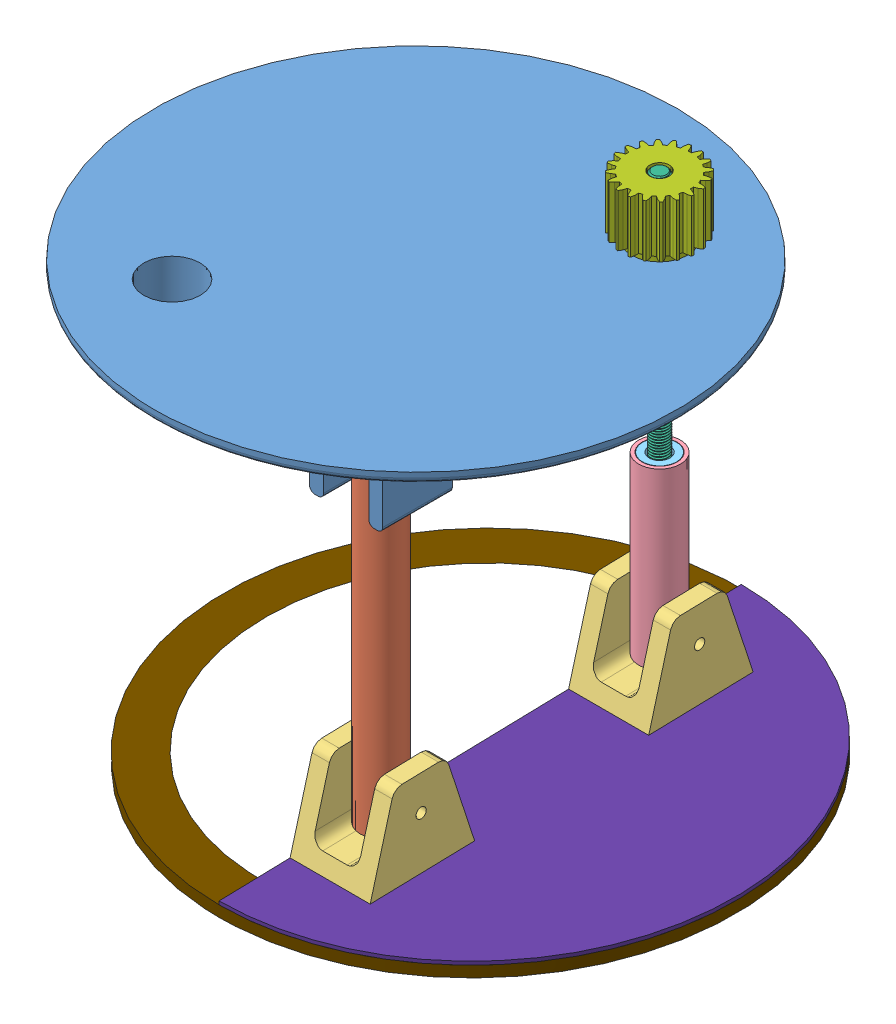
SolidWorks assembly Mıknatıslı lineer yan devirme, configuration Varsayılan. Lengths in mm.
Overall size (168.5 136.91 150.15).
20 component instances, 18 part files, 25 mates.
Components (placement in the parent):
- üst tabla-1: üst tabla [Varsayılan] at (-14.6467 18.8833 150) size (150 23 150)
- 16x100 karbon boru-2: 16x100 karbon boru [Varsayılan] at (15.3533 16.8833 190.0024) x (0 0.000298 -1) z (-1 0 0) size (12 100 12)
- tutturma parçası-5: tutturma parçası [Varsayılan] at (26.8533 -90.112 189.6) x (0 -0.025 0.999687) z (-1 0 0) size (30 25 23)
- tutturma parçası-6: tutturma parçası [Varsayılan] at (26.8533 -88.112 109.625) x (0 -0.025 0.999687) z (-1 0 0) size (30 25 23)
- 12x50-1: 12x50 [Varsayılan] at (15.3533 -81.1167 110) x (0 0 1) z (-1 0 0) size (12 50 12)
- somun yuvası-1: somun yuvası [Varsayılan] at (15.3533 -41.1167 110) x (0.299939 0 -0.953959) z (0.953959 0 0.299939) size (9.8 10 9.8)
- Yivli mil-1: Yivli mil [Varsayılan] at (15.3533 -41.1167 110) x (-0.194357 0 0.980931) z (-0.980931 0 -0.194357) size (5.15 80.6 5.79)
- Z20 pinion Module 1-1: Z20 pinion Module 1 [Default] at (15.3533 28.8833 110) x (0 -1 0) z (0.94071 0 -0.339213) size (26 21.82 21.82)
- inafag_625-2z_6leky27aadc6c6egwocnas8n-1: inafag_625-2z_6leky27aadc6c6egwocnas8n [Default] at (15.3533 7.8833 110) x (0 1 0) z (0.509017 0 0.860756) size (5.01 16 16)
  - inafag_625-2z_6leky27aadc6c6egwocnas8n_01-1: inafag_625-2z_6leky27aadc6c6egwocnas8n_01 [Default] at origin size (5 16 16)
  - inafag_625-2z_6leky27aadc6c6egwocnas8n_02-1: inafag_625-2z_6leky27aadc6c6egwocnas8n_02 [Default] at origin size (5.01 8.5 8.5)
  - inafag_625-2z_6leky27aadc6c6egwocnas8n_03-1: inafag_625-2z_6leky27aadc6c6egwocnas8n_03 [Default] at origin size (3.8 11.99 11.99)
  - inafag_625-2z_6leky27aadc6c6egwocnas8n_04-1: inafag_625-2z_6leky27aadc6c6egwocnas8n_04 [Default] at origin size (4.05 4.13 4.2)
  - inafag_625-2z_6leky27aadc6c6egwocnas8n_05-1: inafag_625-2z_6leky27aadc6c6egwocnas8n_05 [Default] at origin size (3.85 4.1 3.78)
  - inafag_625-2z_6leky27aadc6c6egwocnas8n_06-1: inafag_625-2z_6leky27aadc6c6egwocnas8n_06 [Default] at origin size (3.6 4.12 3.67)
  - inafag_625-2z_6leky27aadc6c6egwocnas8n_07-1: inafag_625-2z_6leky27aadc6c6egwocnas8n_07 [Default] at origin size (4.06 4.14 4.12)
  - inafag_625-2z_6leky27aadc6c6egwocnas8n_08-1: inafag_625-2z_6leky27aadc6c6egwocnas8n_08 [Default] at origin size (0.3 13.2 13.2)
  - inafag_625-2z_6leky27aadc6c6egwocnas8n_09-1: inafag_625-2z_6leky27aadc6c6egwocnas8n_09 [Default] at origin size (0.3 13.2 13.2)
- metal tabla-1: metal tabla [Varsayılan] at (3.8533 -90.1218 149.9894) x (0 0.025 -0.999687) z (1 0 0) size (150 1 75)
- mıknatıs savar-1: mıknatıs savar [Varsayılan] at (3.8533 -90.1218 149.9894) x (1 0 0) z (0 -0.025 0.999687) size (150 7.83 150)
Mates (geometry in assembly coordinates):
- Concentric26: concentric anti-aligned: cylinder of üst tabla-1 through (0.6107 8.8833 190) axis (1 0 0) radius 1.5; cylinder of 16x100 karbon boru-2 through (21.3533 8.8833 190) axis (-1 0 0) radius 1.5
- Concentric29: concentric anti-aligned: cylinder of 16x100 karbon boru-2 through (21.3533 -75.1167 189.975) axis (-1 0 0) radius 1.5; cylinder of tutturma parçası-5 through (3.8533 -75.1167 189.975) axis (1 0 0) radius 1.5
- Distance7: distance = 0.5 mm anti-aligned: plane of tutturma parçası-5 through (8.8533 -84.7386 174.7297) normal (1 0 0); cylinder of 16x100 karbon boru-2 through (15.3533 -83.1167 189.9726) axis (0 1 0.000298) radius 6
- Concentric30: concentric anti-aligned: cylinder of tutturma parçası-6 through (3.8533 -73.1167 110) axis (1 0 0) radius 1.5; cylinder of 12x50-1 through (21.3533 -73.1167 110) axis (-1 0 0) radius 1.5
- Distance8: distance = 0.5 mm anti-aligned: cylinder of 12x50-1 through (15.3533 -31.1167 110) axis (0 -1 0) radius 6; plane of tutturma parçası-6 through (21.8533 -82.7386 94.7547) normal (-1 0 0)
- Concentric31: concentric aligned: cylinder of 12x50-1 through (15.3533 -31.1167 110) axis (0 -1 0) radius 5; cylinder of somun yuvası-1 through (15.3533 -31.1167 110) axis (0 -1 0) radius 4.9
- Coincident1: coincident aligned: plane of 12x50-1 through (15.3533 -31.1167 110) normal (0 1 0); plane of somun yuvası-1 through (15.3533 -31.1167 110) normal (0 1 0)
- Concentric32: concentric anti-aligned: cylinder of üst tabla-1 through (15.3533 7.8833 110) axis (0 1 0) radius 8.1; cylinder of Yivli mil-1 through (15.3533 38.8833 110) axis (0 -1 0) radius 2.5
- Concentric33: concentric anti-aligned: cylinder of somun yuvası-1 through (15.3533 -41.1167 110) axis (0 1 0) radius 3; cylinder of Yivli mil-1 through (15.3533 38.8833 110) axis (0 -1 0) radius 2.5
- Concentric34: concentric aligned: cylinder of Yivli mil-1 through (15.3533 38.8833 110) axis (0 -1 0) radius 2.5; cylinder of Z20 pinion Module 1-1 through (15.3533 12.8833 110) axis (0 -1 0) radius 2.8
- Coincident2: coincident aligned: plane of Yivli mil-1 through (15.3533 38.8833 110) normal (0 1 0); plane of Z20 pinion Module 1-1 through (15.3533 38.8833 110) normal (0 1 0)
- Concentric35: concentric anti-aligned: cylinder of üst tabla-1 through (15.3533 7.8833 110) axis (0 1 0) radius 8.1; cylinder of inafag_625-2z_6leky27aadc6c6egwocnas8n-1/inafag_625-2z_6leky27aadc6c6egwocnas8n_01-1 through (15.3533 10.3833 110) axis (0 -1 0) radius 8
- Parallel1: parallel aligned: plane of tutturma parçası-5 through (3.8533 -89.737 174.6047) normal (0 -0.999687 -0.025); plane of tutturma parçası-6 through (3.8533 -87.737 94.6297) normal (0 -0.999687 -0.025)
- Coincident8: coincident anti-aligned: plane of Z20 pinion Module 1-1 through (15.3533 12.8833 110) normal (0 -1 0); plane of inafag_625-2z_6leky27aadc6c6egwocnas8n-1/inafag_625-2z_6leky27aadc6c6egwocnas8n_02-1 through (17.1476 12.8833 113.0342) normal (0 1 0)
- Coincident9: coincident anti-aligned: plane of üst tabla-1 through (15.3533 7.8833 110) normal (0 1 0); plane of inafag_625-2z_6leky27aadc6c6egwocnas8n-1/inafag_625-2z_6leky27aadc6c6egwocnas8n_01-1 through (18.9928 7.8833 116.1544) normal (0 -1 0)
- Parallel3: parallel aligned: plane of tutturma parçası-5 through (3.8533 -67.9872 184.8837) normal (-1 0 0); plane of tutturma parçası-6 through (3.8533 -65.9872 104.9087) normal (-1 0 0)
- Coincident13: coincident anti-aligned: plane of tutturma parçası-5 through (3.8533 -89.737 174.6047) normal (0 -0.999687 -0.025); plane of metal tabla-1 through (3.8533 -89.1221 150.0144) normal (0 0.999687 0.025)
- Coincident14: coincident anti-aligned: plane of tutturma parçası-6 through (3.8533 -87.737 94.6297) normal (0 -0.999687 -0.025); plane of metal tabla-1 through (3.8533 -89.1221 150.0144) normal (0 0.999687 0.025)
- Coincident17: coincident aligned: plane of tutturma parçası-6 through (3.8533 -65.9872 104.9087) normal (-1 0 0); plane of metal tabla-1 through (3.8533 -90.9971 224.9909) normal (-1 0 0)
- Distance12: distance = 50 mm: line of tutturma parçası-5 through (3.8533 -89.737 174.6047) axis (1 0 0); line of tutturma parçası-6 through (3.8533 -88.487 124.6203) axis (1 0 0)
- Distance13: distance = 23.4199 mm: point of metal tabla-1; moEndPointRef_w of tutturma parçası-5
- LimitDistance3: limit distance = 0 mm aligned: plane of somun yuvası-1 through (15.3533 -41.1167 110) normal (0 -1 0); plane of Yivli mil-1 through (15.3533 -41.1167 110) normal (0 -1 0)
- Distance14: distance = 0.5 mm anti-aligned: plane of üst tabla-1 through (8.8533 -1.1167 200) normal (1 0 0); cylinder of 16x100 karbon boru-2 through (15.3533 -83.1167 189.9726) axis (0 1 0.000298) radius 6
- Coincident19: coincident anti-aligned: plane of metal tabla-1 through (3.8533 -90.1218 149.9894) normal (0 -0.999687 -0.025); plane of mıknatıs savar-1 through (-71.1467 -90.1218 149.9894) normal (0 0.999687 0.025)
- Concentric36: concentric anti-aligned: cylinder of metal tabla-1 through (3.8533 -89.1221 150.0144) axis (0 -0.999687 -0.025) radius 75; cylinder of mıknatıs savar-1 through (3.8533 -52.0318 150.9419) axis (0 0.999687 0.025) radius 75
